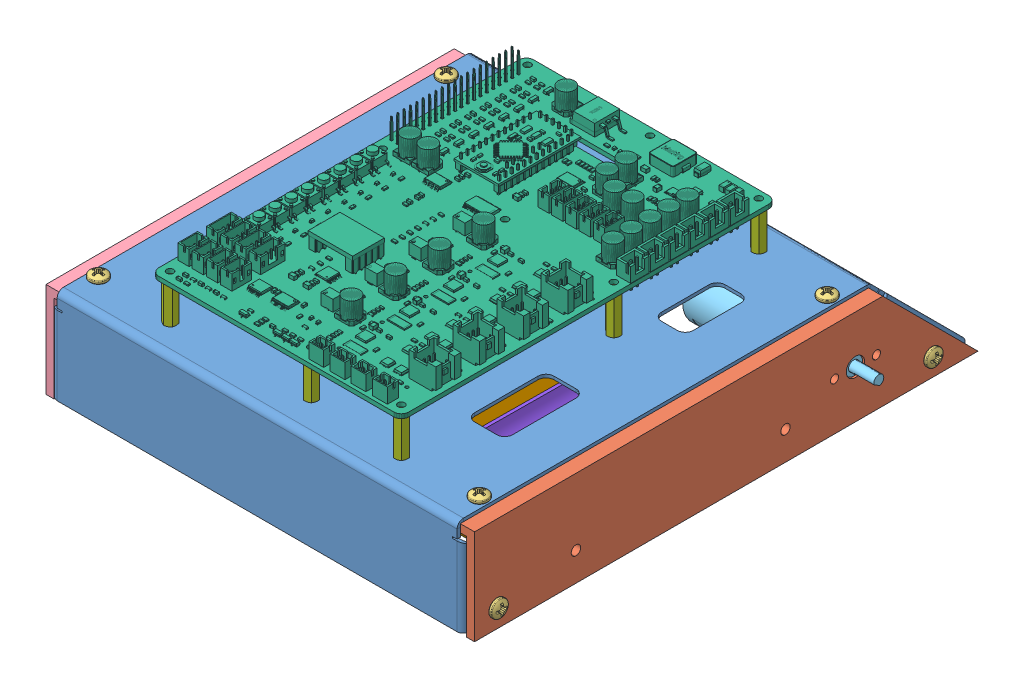
SolidWorks assembly Body with Control Board, configuration Default. Lengths in mm.
Overall size (190.1 70.48 202.7).
28 component instances, 9 part files, 54 mates.
Components (placement in the parent):
- Steel-1: Steel [Default] at (90.7433 96.2384 11.0735) size (165.11 38.1 202.31)
- AngleAlum-1: AngleAlum [Default] at (93.9183 116.5672 73.779) x (1 0 0) z (0 1 0) size (19.69 201.42 38.1)
- 91735A144-1: 91735A144 [91735A144] at (87.5683 86.0872 -109.101) x (0 -1 0) z (1 0 0) size (6.86 6.86 8.86)
- 91735A144-2: 91735A144 [91735A144] at (-68.0067 111.4872 62.349) x (1 0 0) z (0 1 0) size (6.86 6.86 8.86)
- 91735A144-3: 91735A144 [91735A144] at (84.3933 111.4872 -76.8249) x (1 0 0) z (0 1 0) size (6.86 6.86 8.86)
- AngleAlum2-1: AngleAlum2 [Default] at (-77.5317 116.5672 73.779) x (0 1 0) z (-1 0 0) size (38.1 201.42 19.69)
- 91735A144-5: 91735A144 [91735A144] at (84.3933 111.4872 62.349) x (1 0 0) z (0 1 0) size (6.86 6.86 8.86)
- 91735A144-6: 91735A144 [91735A144] at (-71.1817 86.0872 64.889) x (0 1 0) z (-1 0 0) size (6.86 6.86 8.86)
- 91735A144-7: 91735A144 [91735A144] at (-68.0067 111.4872 -76.8249) x (1 0 0) z (0 1 0) size (6.86 6.86 8.86)
- 91735A144-8: 91735A144 [91735A144] at (-71.1817 86.0872 -109.101) x (0 1 0) z (-1 0 0) size (6.86 6.86 8.86)
- 91735A144-9: 91735A144 [91735A144] at (87.5683 86.0872 64.889) x (0 -1 0) z (1 0 0) size (6.86 6.86 8.86)
- 25d-metal-gearmotor-75-99-1: 25d-metal-gearmotor-75-99 [Default] at (-55.9817 68.9817 -90.4106) x (0 0.924225 0.381849) z (-1 0 0) size (25 25 70.5)
- 25d-metal-gearmotor-75-99-2: 25d-metal-gearmotor-75-99 [Default] at (72.3683 81.3488 -104.924) x (0 0.523673 0.851919) z (1 0 0) size (25 25 70.5)
- Motor_Control_Board-2: Motor_Control_Board [Default] at (156.1906 135.5286 109.3653) x (0.000065 0 -1) z (0 1 0) size (150.02 100.02 20.09)
- 98952A113-1: 98952A113 [98952A113] at (-38.3064 123.8872 63.3527) x (0 -1 0) z (0.480217 0 0.877149) size (20.19 5.2 4.5)
- 98952A113-2: 98952A113 [98952A113] at (16.1937 123.8872 61.3563) x (0 -1 0) z (0.969858 0 0.243669) size (20.19 5.2 4.5)
- 98952A113-3: 98952A113 [98952A113] at (-38.301 123.8872 -21.6473) x (0 -1 0) z (0.969858 0 0.243669) size (20.19 5.2 4.5)
- 98952A113-4: 98952A113 [98952A113] at (10.7028 123.8872 -79.6441) x (0 -1 0) z (0.969858 0 0.243669) size (20.19 5.2 4.5)
- 98952A113-5: 98952A113 [98952A113] at (54.199 123.8872 -21.6413) x (0 -1 0) z (0.969858 0 0.243669) size (20.19 5.2 4.5)
- 98952A113-6: 98952A113 [98952A113] at (-38.2972 123.8872 -79.6473) x (0 -1 0) z (0.969858 0 0.243669) size (20.19 5.2 4.5)
- 98952A113-7: 98952A113 [98952A113] at (10.699 123.8872 -21.6441) x (0 -1 0) z (0.969858 0 0.243669) size (20.19 5.2 4.5)
- 98952A113-8: 98952A113 [98952A113] at (54.1936 123.8872 63.3587) x (0 -1 0) z (0.969858 0 0.243669) size (20.19 5.2 4.5)
- 98952A113-9: 98952A113 [98952A113] at (54.2028 123.8872 -79.6413) x (0 -1 0) z (0.969858 0 0.243669) size (20.19 5.2 4.5)
- keystone-PN1047-1: keystone-PN1047 [Default] at (59.4767 78.4672 -8.626) x (0.999962 0 0.008727) z (-0.008727 0 0.999962) size (39.78 18.43 81.03)
- keystone-PN1047-2: keystone-PN1047 [Default] at (19.1415 78.4672 -8.626) x (0.999962 0 0.008727) z (-0.008727 0 0.999962) size (39.78 18.43 81.03)
- keystone-PN1047-3: keystone-PN1047 [Default] at (-21.1937 78.4672 -8.626) x (0.999962 0 0.008727) z (-0.008727 0 0.999962) size (39.78 18.43 81.03)
- keystone-PN1047-4: keystone-PN1047 [Default] at (-61.5289 78.4672 -8.626) x (0.999962 0 0.008727) z (-0.008727 0 0.999962) size (39.78 18.43 81.03)
- Battery Plate-1: Battery Plate [Default] at (-77.5317 78.4672 73.779) x (-1 0 0) z (0 -1 0) size (165.1 95.25 20.32)
Mates (geometry in assembly coordinates):
- Coincident13: coincident anti-aligned: plane of AngleAlum2-1 through (-77.5317 116.5672 -129.421) normal (-1 0 0); plane of 91735A144-6 through (-77.5317 86.0872 64.889) normal (1 0 0)
- Coincident15: coincident anti-aligned: plane of AngleAlum-1 through (93.9183 78.4672 -129.421) normal (1 0 0); plane of 91735A144-1 through (93.9183 86.0872 -109.101) normal (-1 0 0)
- Coincident16: coincident anti-aligned: plane of AngleAlum-1 through (93.9183 78.4672 -129.421) normal (1 0 0); plane of 91735A144-9 through (93.9183 86.0872 64.889) normal (-1 0 0)
- Coincident18: coincident anti-aligned: plane of AngleAlum2-1 through (-74.3567 78.4672 -129.421) normal (1 0 0); plane of 25d-metal-gearmotor-75-99-1 through (-74.3567 97.5172 -78.621) normal (-1 0 0)
- Coincident19: coincident anti-aligned: plane of AngleAlum-1 through (90.7433 113.3922 -129.421) normal (-1 0 0); plane of 25d-metal-gearmotor-75-99-2 through (90.7433 97.5172 -78.621) normal (1 0 0)
- Concentric1: concentric anti-aligned: circle of 25d-metal-gearmotor-75-99-1; circle of 25d-metal-gearmotor-75-99-2
- Concentric3: concentric anti-aligned: circle of AngleAlum-1; circle of 25d-metal-gearmotor-75-99-2
- Coincident35: coincident anti-aligned: plane of Steel-1 through (90.7433 116.5672 -152.4241) normal (1 0 0); plane of AngleAlum-1 through (90.7433 113.3922 -129.421) normal (-1 0 0)
- Coincident36: coincident anti-aligned: plane of Steel-1 through (-74.3567 116.5672 73.779) normal (0 -1 0); plane of AngleAlum-1 through (93.9183 116.5672 -129.421) normal (0 1 0)
- Coincident37: coincident anti-aligned: plane of Steel-1 through (-74.3567 116.5672 -152.4241) normal (-1 0 0); plane of AngleAlum2-1 through (-74.3567 78.4672 -129.421) normal (1 0 0)
- Coincident38: coincident anti-aligned: plane of Steel-1 through (-74.3567 116.5672 73.779) normal (0 -1 0); plane of AngleAlum2-1 through (-57.8467 116.5672 -129.421) normal (0 1 0)
- Coincident39: coincident anti-aligned: plane of Steel-1 through (-74.3567 79.7372 73.779) normal (0 0 -1); plane of AngleAlum2-1 through (-77.5317 116.5672 73.779) normal (0 0 1)
- Concentric4: concentric anti-aligned: circle of AngleAlum2-1; circle of 91735A144-6
- Concentric5: concentric anti-aligned: cylinder of AngleAlum-1 through (93.9183 86.0872 -109.101) axis (-1 0 0) radius 1.8986; circle of 91735A144-1
- Concentric6: concentric aligned: cylinder of Steel-1 through (89.4733 86.0872 64.889) axis (1 0 0) radius 1.7526; circle of 91735A144-9
- Parallel1: parallel anti-aligned: plane of Steel-1 through (-74.3567 117.8372 73.779) normal (0 1 0); plane of Motor_Control_Board-2 through (58.2028 133.8372 -79.641) normal (0 -1 0)
- Distance4: distance = 6.35 mm: plane of assembly through (0 0 -88.9989) normal (0 0 1); moEndPointRef_w of Motor_Control_Board-2
- Concentric7: concentric anti-aligned: circle of Steel-1; circle of 98952A113-1
- Coincident47: coincident anti-aligned: plane of Steel-1 through (-74.3567 117.8372 73.779) normal (0 1 0); plane of 98952A113-1 through (-36.0275 117.8372 62.1051) normal (0 -1 0)
- Concentric8: concentric anti-aligned: circle of Steel-1; circle of 98952A113-3
- Concentric9: concentric anti-aligned: circle of Steel-1; circle of 98952A113-6
- Concentric10: concentric anti-aligned: circle of Steel-1; circle of 98952A113-7
- Concentric11: concentric anti-aligned: circle of Steel-1; circle of 98952A113-2
- Concentric12: concentric anti-aligned: circle of Steel-1; circle of 98952A113-4
- Concentric13: concentric anti-aligned: circle of Steel-1; circle of 98952A113-8
- Concentric14: concentric anti-aligned: circle of Steel-1; circle of 98952A113-5
- Concentric15: concentric anti-aligned: circle of Steel-1; circle of 98952A113-9
- Coincident48: coincident anti-aligned: plane of Steel-1 through (-74.3567 117.8372 73.779) normal (0 1 0); plane of 98952A113-3 through (-37.6679 117.8372 -24.167) normal (0 -1 0)
- Coincident49: coincident anti-aligned: plane of Steel-1 through (-74.3567 117.8372 73.779) normal (0 1 0); plane of 98952A113-6 through (-37.6641 117.8372 -82.167) normal (0 -1 0)
- Coincident50: coincident anti-aligned: plane of Steel-1 through (-74.3567 117.8372 73.779) normal (0 1 0); plane of 98952A113-4 through (11.3359 117.8372 -82.1639) normal (0 -1 0)
- Coincident51: coincident anti-aligned: plane of Steel-1 through (-74.3567 117.8372 73.779) normal (0 1 0); plane of 98952A113-9 through (54.8359 117.8372 -82.161) normal (0 -1 0)
- Coincident52: coincident anti-aligned: plane of Steel-1 through (-74.3567 117.8372 73.779) normal (0 1 0); plane of 98952A113-5 through (54.8321 117.8372 -24.161) normal (0 -1 0)
- Coincident53: coincident anti-aligned: plane of Steel-1 through (-74.3567 117.8372 73.779) normal (0 1 0); plane of 98952A113-8 through (54.8266 117.8372 60.839) normal (0 -1 0)
- Coincident54: coincident anti-aligned: plane of Steel-1 through (-74.3567 117.8372 73.779) normal (0 1 0); plane of 98952A113-2 through (16.8267 117.8372 58.8365) normal (0 -1 0)
- Coincident55: coincident anti-aligned: plane of Steel-1 through (-74.3567 117.8372 73.779) normal (0 1 0); plane of 98952A113-7 through (11.3321 117.8372 -24.1639) normal (0 -1 0)
- Coincident56: coincident anti-aligned: plane of Motor_Control_Board-2 through (58.2028 133.8372 -79.641) normal (0 -1 0); plane of 98952A113-1 through (-36.0275 133.8372 62.1051) normal (0 1 0)
- Coincident57: coincident anti-aligned: plane of Steel-1 through (-74.3567 117.8372 73.779) normal (0 1 0); plane of 91735A144-5 through (84.3933 117.8372 62.349) normal (0 -1 0)
- Coincident58: coincident anti-aligned: plane of Steel-1 through (-74.3567 117.8372 73.779) normal (0 1 0); plane of 91735A144-3 through (84.3933 117.8372 -76.8249) normal (0 -1 0)
- Coincident59: coincident anti-aligned: plane of Steel-1 through (-74.3567 117.8372 73.779) normal (0 1 0); plane of 91735A144-2 through (-68.0067 117.8372 62.349) normal (0 -1 0)
- Concentric16: concentric anti-aligned: circle of AngleAlum2-1; circle of 91735A144-8
- Coincident61: coincident anti-aligned: plane of AngleAlum2-1 through (-77.5317 116.5672 -129.421) normal (-1 0 0); plane of 91735A144-8 through (-77.5317 86.0872 -109.101) normal (1 0 0)
- Coincident62: coincident anti-aligned: plane of Steel-1 through (-74.3567 117.8372 73.779) normal (0 1 0); plane of 91735A144-7 through (-68.0067 117.8372 -76.8249) normal (0 -1 0)
- InPlace1: in place: plane of ? through (-77.5317 46.0016 -129.421) normal (0 -1 0); plane of ? through (0 46.0016 0) normal (0 -1 0); moOrthogonalPlaneRef_w of ? through (-77.5317 46.0016 -129.421) normal (0 -1 0); unknown of ?; plane of ? through (-77.5317 46.0016 -129.421) normal (0 -1 0); line of ? through (-55 0 46.0016) axis (0 -1 0); plane of AngleAlum2-1 through (-77.5317 78.4672 -129.421) normal (0 -1 0); unknown of Battery Plate-1
- Coincident63: coincident aligned: plane of AngleAlum2-1; plane of Battery Plate-1
- Coincident64: coincident aligned: moOrthogonalPlaneRef_w of AngleAlum2-1 through (-77.5317 78.4672 73.779) normal (0 0 -1); plane of Battery Plate-1
- Coincident65: coincident anti-aligned: moOrthogonalPlaneRef_w of AngleAlum2-1 through (-77.5317 78.4672 73.779) normal (1 0 0); plane of Battery Plate-1
- Concentric17: concentric aligned: circle of keystone-PN1047-4; circle of Battery Plate-1
- Coincident67: coincident anti-aligned: plane of keystone-PN1047-4 through (-72.1542 78.4672 25.725) normal (0 -1 0); plane of Battery Plate-1 through (-77.5317 78.4672 73.779) normal (0 1 0)
- Concentric18: concentric aligned: circle of keystone-PN1047-3; circle of Battery Plate-1
- Coincident68: coincident anti-aligned: plane of keystone-PN1047-3 through (-31.819 78.4672 25.725) normal (0 -1 0); plane of Battery Plate-1 through (-77.5317 78.4672 73.779) normal (0 1 0)
- Concentric19: concentric aligned: circle of keystone-PN1047-2; circle of Battery Plate-1
- Coincident69: coincident anti-aligned: plane of keystone-PN1047-2 through (8.5162 78.4672 25.725) normal (0 -1 0); plane of Battery Plate-1 through (-77.5317 78.4672 73.779) normal (0 1 0)
- Concentric20: concentric aligned: circle of keystone-PN1047-1; circle of Battery Plate-1
- Coincident70: coincident anti-aligned: plane of keystone-PN1047-1 through (48.8514 78.4672 25.725) normal (0 -1 0); plane of Battery Plate-1 through (-77.5317 78.4672 73.779) normal (0 1 0)
